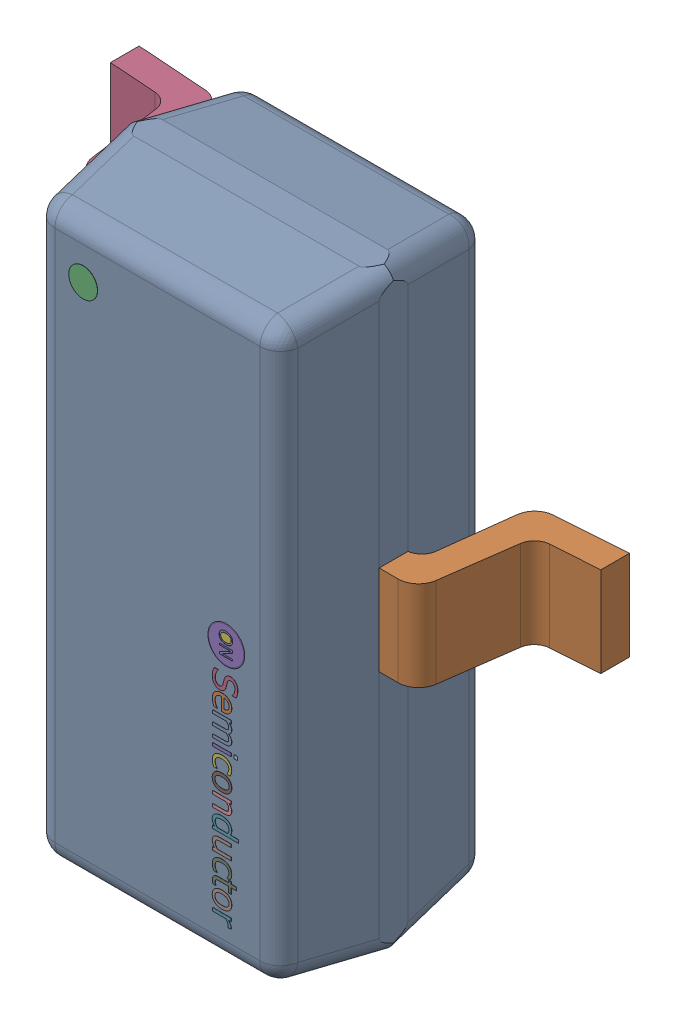
SolidWorks assembly Q5.step, configuration Default. Lengths in mm.
Overall size (2.4 2.9 1.11).
5 component instances, 4 part files, 0 mates.
Components (placement in the parent):
- IC_ON_Semiconductor_NUD3112LT1G_eec.step-1: IC_ON_Semiconductor_NUD3112LT1G_eec.step [Default] at (17.9402 3.368 0) size (2.4 2.9 1.11)
  - 1-5.step-1: 1-5.step [Default] at (0 0 0.1) x (0 1 0) z (0 0 1) size (2.9 1.3 1.01)
  - 2-6.step-1: 2-6.step [Default] x (-1 0 0) z (0 1 0) size (2.4 0.68 2.34)
  - ON Semi Logo - withoutPN.step-1: ON Semi Logo - withoutPN.step [Default] at (-0.2581 -0.9018 1.011) x (-1 0 0) z (0 0 1) size (0.19 0.19 0.1)
  - ON Semi Logo - withoutPN - Copy.step-1: ON Semi Logo - withoutPN - Copy.step [Default] at (-0.2645 -0.8914 1.011) x (-1 0 0) z (0 0 1) size (0.83 2.45 0.1)
